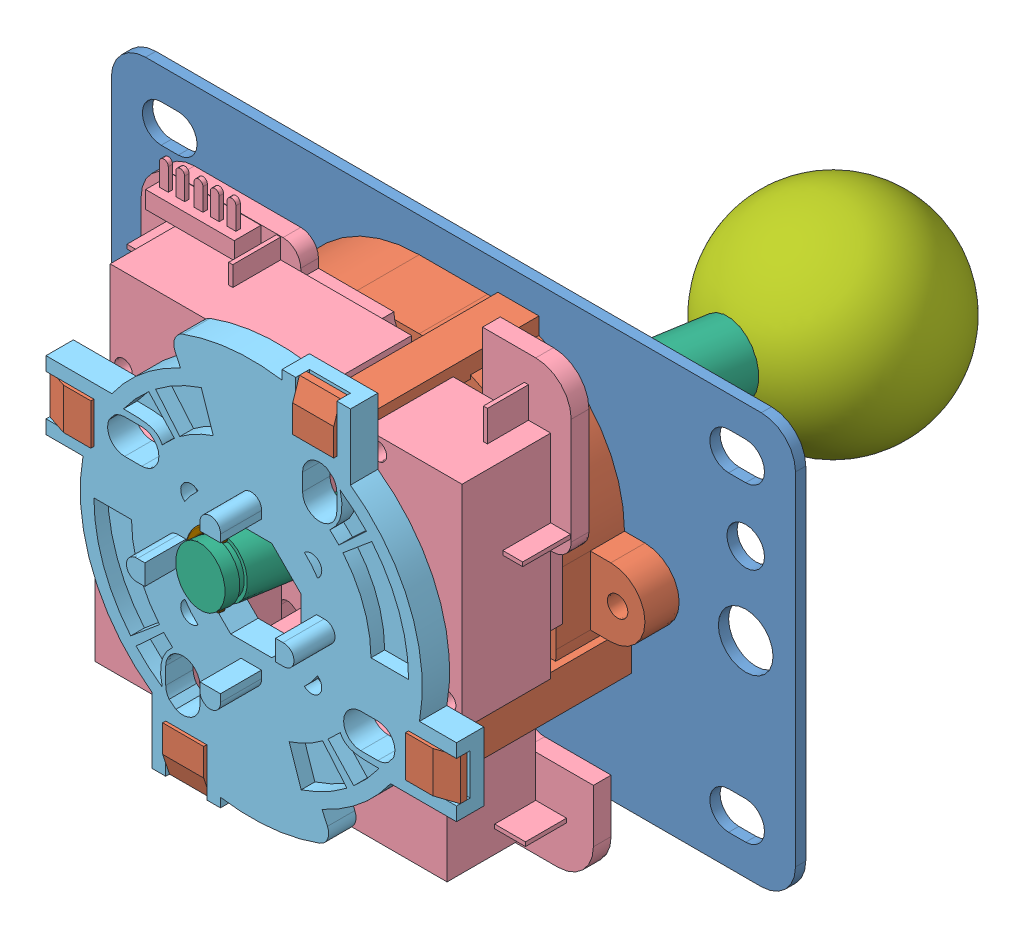
SolidWorks assembly joystick, configuration Défaut. Lengths in mm.
Overall size (100 66.68 103.45).
9 component instances, 9 part files, 0 mates.
Components (placement in the parent):
- SANWA_JOYSTICK_3-1: SANWA_JOYSTICK_3 [Défaut] at origin size (100 60 1.5)
- SSANWA_JOYSTICK_6-1: SSANWA_JOYSTICK_6 [Défaut] at origin size (66 60 30)
- SANWA_JOYSTICK_2-1: SANWA_JOYSTICK_2 [Défaut] x (1 0 0) z (0 1 0) size (39.99 20.68 39.98)
- SANWA_JOYSTICK_5-1: SANWA_JOYSTICK_5 [Défaut] at (0 0 12.592) x (1 0 0) z (0 0 -1) size (66.1 66.68 17.11)
- GT-Y-1: GT-Y [Défaut] at (0 0 27.552) size (60 60 10)
- SANWA_JOYSTICK_0-1: SANWA_JOYSTICK_0 [Défaut] x (-0.317284 -0.947951 0.026831) z (0.943635 -0.312775 0.10828) size (10 85 10)
- BALL-1: BALL [Défaut] at (4.8068 -3.0434 -50.6817) x (0.995532 0 0.09442) z (0.005634 0.998218 -0.059407) size (30 30 30)
- DUSTER-1: DUSTER [Défaut] at (0 0 -2) x (-1 0 0) z (0 0 1) size (40 40 0.5)
- E-1: E [Défaut] at (-2.9689 1.8797 31.3034) x (0.995532 0 0.09442) z (0.005634 0.998218 -0.059407) size (5.88 1.1 10)
